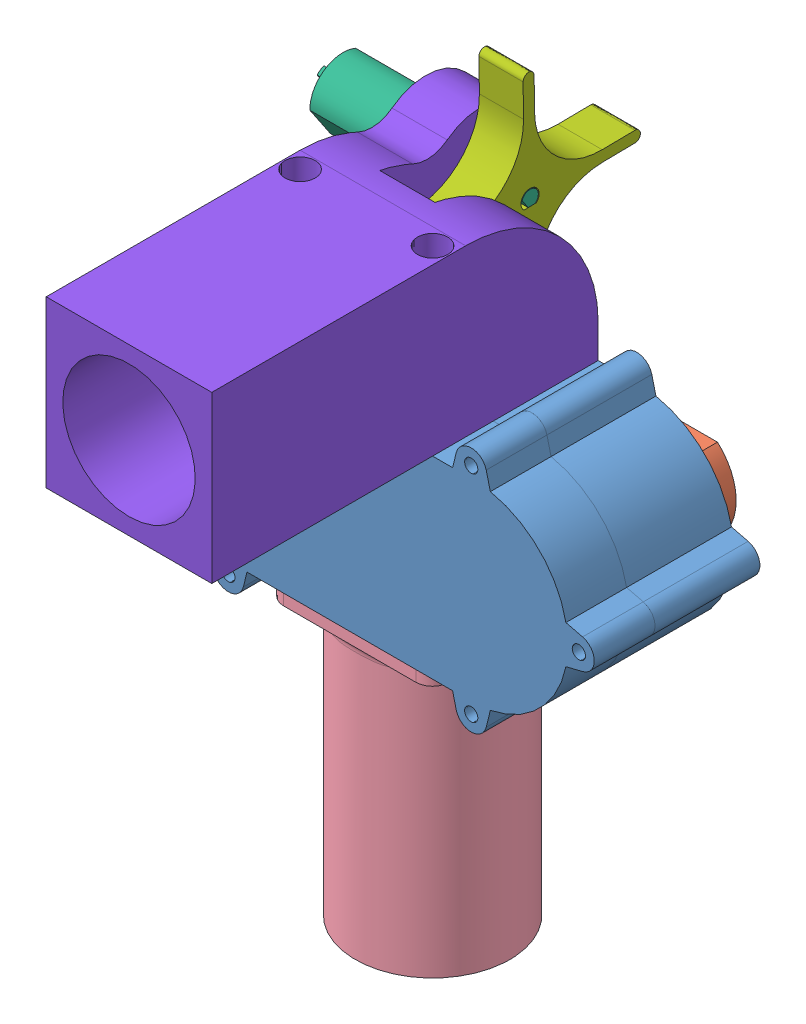
SolidWorks assembly Assemblage_propulseur, configuration Défaut. Lengths in mm.
Overall size (88.6 127.7 89.03).
12 component instances, 10 part files, 34 mates.
Components (placement in the parent):
- Propulseur-2: Propulseur [Défaut] at origin size (88.6 44.6 30)
- Moteur-1: Moteur [Défaut] at (-22 0 -8) size (20 15 35)
- Roue-1: Roue [Défaut] at (-22 0 25) x (-0.209332 -0.977845 0) z (0 0 -1) size (29.49 29.48 20)
- Roue-2: Roue [Défaut] at (22 0 25) x (0.018167 -0.999835 0) z (0 0 -1) size (29.49 29.48 20)
- Moteur-2: Moteur [Défaut] at (22 0 -8) size (20 15 35)
- Tube-1: Tube [Défaut] at (0 -17.5 15) x (1 0 0) z (0 -1 0) size (30 30 52)
- Tube_Coudee-1: Tube_Coudee [Défaut] at (0 17.5 15) x (-1 0 0) z (0 1 0) size (30 65 66.5) (hidden)
- Bille-1: Bille [Défaut] at (0 32.5 40.7569) x (0.918497 -0.273761 -0.285338) z (-0.03248 -0.771387 0.635537) size (22.22 22.22 22.22)
- DC_Gear_Motor-1: DC_Gear_Motor [Défaut] at (-30 45.7016 0.4476) x (1 0 0) z (0 -0.829112 -0.559082) size (35.6 10 12.25)
- pale-1: pale [Défaut] at (-4.1 37.9302 1.2406) x (0 0.239039 0.97101) z (1 0 0) size (34.91 30.5 8) (hidden)
- pale 4 ailes-1: pale 4 ailes [Défaut] at (-4.1 37.9302 1.2406) x (0 -0.013826 0.999904) z (1 0 0) size (40 40 8)
- Tube+Servo2-1: Tube+Servo2 [Défaut] at (0 17.5 0) x (-1 0 0) z (0 1 0) size (30 78.74 30.42)
Mates (geometry in assembly coordinates):
- Coaxiale3: concentric: cylinder of Propulseur-2 through (-22 0 30) axis (0 0 -1) radius 10.15; cylinder of Moteur-1 through (-22 0 17) axis (0 0 -1) radius 10
- Parallèle2: parallel: plane of Propulseur-2 through (-15.3292 7.65 30) normal (0 -1 0); plane of Moteur-1 through (-28.6144 7.5 17) normal (0 1 0)
- Coaxiale4: concentric: cylinder of Moteur-1 through (-22 0 19) axis (0 0 -1) radius 3; cylinder of Roue-1 through (-22 0 5) axis (0 0 1) radius 1
- Coaxiale5: concentric: cylinder of Propulseur-2 through (22 0 30) axis (0 0 -1) radius 10.15; cylinder of Moteur-2 through (22 0 17) axis (0 0 -1) radius 10
- Parallèle3: parallel: plane of Propulseur-2 through (15.3292 7.65 30) normal (0 -1 0); plane of Moteur-2 through (15.3856 7.5 17) normal (0 1 0)
- Coaxiale6: concentric: cylinder of Roue-2 through (22 0 5) axis (0 0 1) radius 1; cylinder of Moteur-2 through (22 0 19) axis (0 0 -1) radius 3
- Coaxiale10: concentric: cylinder of Moteur-1 through (-22 0 27) axis (0 0 -1) radius 1; cylinder of Roue-1 through (-22 0 5) axis (0 0 1) radius 1
- Distance1: distance = 1 mm: plane of Moteur-1 through (-22 0 19) normal (0 0 1); plane of Roue-1 through (-22 0 20) normal (0 0 -1)
- Coïncidente1: coincident: plane of Propulseur-2 through (0 0 17) normal (0 0 -1); plane of Moteur-2 through (22 0 17) normal (0 0 1)
- Distance2: distance = 1 mm: plane of Roue-2 through (22 0 20) normal (0 0 -1); plane of Moteur-2 through (22 0 19) normal (0 0 1)
- Coïncidente3: coincident: plane of Propulseur-2 through (0 0 17) normal (0 0 -1); plane of Moteur-1 through (-22 0 17) normal (0 0 1)
- Coïncidente4: coincident: plane of Propulseur-2 through (-22 -17.5 30) normal (0 -1 0); plane of Tube-1 through (0 -17.5 15) normal (0 1 0)
- Coaxiale11: concentric: cylinder of Propulseur-2 through (12 17.501 3) axis (0 -1 0) radius 1; cylinder of Tube-1 through (12 -19.5 3) axis (0 1 0) radius 1.5
- Coaxiale12: concentric: cylinder of Propulseur-2 through (-12 17.501 3) axis (0 -1 0) radius 1; cylinder of Tube-1 through (-12 -19.5 3) axis (0 1 0) radius 1.5
- Coïncidente5: coincident: plane of Propulseur-2 through (-22 17.5 30) normal (0 1 0); plane of Tube_Coudee-1 through (0 17.5 15) normal (0 -1 0)
- Coaxiale13: concentric: cylinder of Propulseur-2 through (-12 -17.501 27) axis (0 1 0) radius 1; cylinder of Tube_Coudee-1 through (-12 20.5 27) axis (0 -1 0) radius 1.5
- Coaxiale14: concentric: cylinder of Propulseur-2 through (-12 -17.501 3) axis (0 1 0) radius 1; cylinder of Tube_Coudee-1 through (-12 20.5 3) axis (0 -1 0) radius 1.5
- Coïncidente14: coincident: point of ?
- Coïncidente15: coincident: sphere of ?
- Coïncidente19: coincident: unknown of ?
- Contrainte de trajectoire2: path: point of Bille-1; curve of assembly; curve of assembly
- Tangent6: tangent: sphere of Bille-1; cylinder of pale-1 through (3.9 32.7767 16.1011) axis (-1 0 0) radius 1
- Coaxiale18: concentric: cylinder of DC_Gear_Motor-1 through (-5.5 37.9302 1.2406) axis (1 0 0) radius 1.5; cylinder of pale-1 through (3.9 37.9302 1.2406) axis (-1 0 0) radius 1.65
- Parallèle4: parallel: plane of DC_Gear_Motor-1; plane of pale-1
- Coïncidente21: coincident: plane of DC_Gear_Motor-1 through (3.9 38.084 1.0126) normal (1 0 0); plane of pale-1 through (3.9 19.481 5.7823) normal (1 0 0)
- Coaxiale19: concentric: cylinder of DC_Gear_Motor-1 through (-5.5 37.9302 1.2406) axis (1 0 0) radius 1.5; cylinder of pale 4 ailes-1 through (3.9 37.9302 1.2406) axis (-1 0 0) radius 1.65
- Coïncidente22: coincident: plane of DC_Gear_Motor-1 through (3.9 38.084 1.0126) normal (1 0 0); plane of pale 4 ailes-1 through (3.9 18.932 0.9779) normal (1 0 0)
- Tangent7: tangent: sphere of Bille-1; cylinder of pale 4 ailes-1 through (3.9 19.2063 4.4679) axis (-1 0 0) radius 1
- Coïncidente23: coincident: plane of Propulseur-2 through (-22 17.5 30) normal (0 1 0); plane of Tube+Servo2-1 through (0 17.5 0) normal (0 -1 0)
- Coaxiale20: concentric: cylinder of Propulseur-2 through (-12 -17.501 27) axis (0 1 0) radius 1; cylinder of Tube+Servo2-1 through (-12 47.5 27) axis (0 -1 0) radius 1.6
- Coaxiale21: concentric: cylinder of Propulseur-2 through (12 -17.501 27) axis (0 1 0) radius 1; cylinder of Tube+Servo2-1 through (12 47.5 27) axis (0 -1 0) radius 1.6
- Distance3: distance = 0.1 mm: plane of DC_Gear_Motor-1 through (-6.8 40.1082 8.7426) normal (0 -0.559082 0.829112); plane of Tube+Servo2-1 through (-6 40.0523 8.8255) normal (0 0.559082 -0.829112)
- Distance4: distance = 0.1 mm: plane of DC_Gear_Motor-1 through (-6.8 30.1588 2.0336) normal (0 -0.829112 -0.559082); plane of Tube+Servo2-1 through (-6 30.02 2.0606) normal (0 0.829112 0.559082)
- Coïncidente26: coincident: plane of DC_Gear_Motor-1 through (-6 37.9302 1.2406) normal (1 0 0); plane of Tube+Servo2-1 through (-6 17.5 0) normal (-1 0 0)
